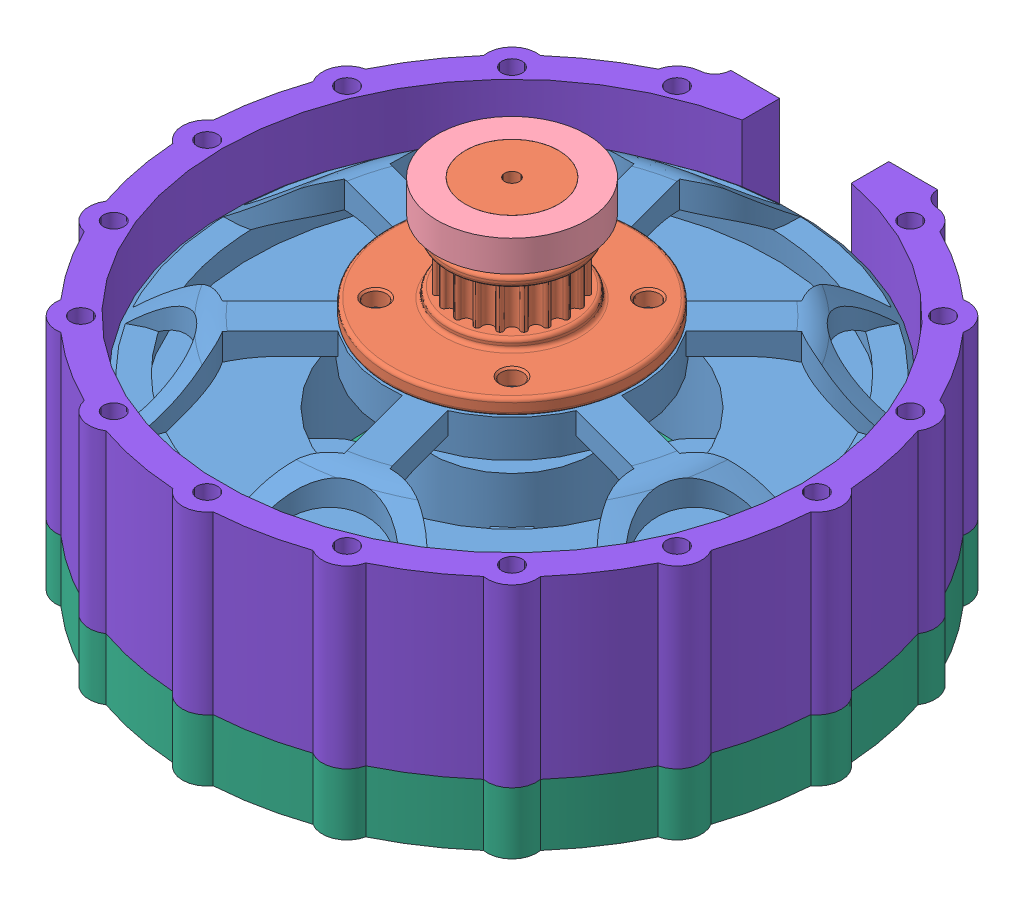
SolidWorks assembly Motor Assem, configuration Default. Lengths in mm.
Overall size (129.63 57.83 129.63).
8 component instances, 8 part files, 16 mates.
Components (placement in the parent):
- 9225 160kv-1: 9225 160kv [Default] at (0 -18.055 0) x (0.707107 0 0.707107) z (-0.707107 0 0.707107) size (91.66 44.53 91.66)
- 15 tooth htd 3mm pulley-1: 15 tooth htd 3mm pulley [Default] at (0 21.7525 0) x (0.707107 0 0.707107) z (-0.707107 0 0.707107) size (39.69 19.3 39.69)
- Encoder Magnet-1: Encoder Magnet [Default] at (0 -19.6425 0) size (6.35 3.17 6.35)
- Bearing 15_24_5mm-1: Bearing 15_24_5mm [Default] at (0 30.9275 0) size (24 5 24)
- Magnut hex puck-1: Magnut hex puck [Default] at (0 -18.055 0) x (0.707107 0 0.707107) z (-0.707107 0 0.707107) size (22.91 4.76 22.91)
- Motor Bracket Base-1: Motor Bracket Base [Default] at origin size (105.95 14.23 104.77)
- encoder final board-1: encoder final board [Default] at (0 -23.0237 -0.3766) x (0 0 -1) z (1 0 0) size (25.25 2.95 25)
- Part1-1: Part1 [Default] at origin size (105.95 28.25 104.77)
Mates (geometry in assembly coordinates):
- Coincident6: coincident anti-aligned: plane of 9225 160kv-1 through (0 -18.055 0) normal (0 -1 0); circle of Encoder Magnet-1
- Concentric2: concentric aligned: cylinder of Encoder Magnet-1 through (0 -18.055 0) axis (0 -1 0) radius 3.175
- Coincident7: coincident aligned: plane of Encoder Magnet-1 through (0 -19.6425 0) normal (0 0 1)
- Concentric4: concentric anti-aligned: cylinder of 9225 160kv-1 through (0 20.125 0) axis (0 1 0) radius 45.83
- Parallel2: parallel anti-aligned: plane of 9225 160kv-1 through (-3.25 -24.405 -36.33) normal (0 0 -1)
- Symmetric1: symmetric aligned: plane of 9225 160kv-1 through (22.981 14.125 22.981) normal (0 1 0); plane of 9225 160kv-1 through (6.8236 -14.125 6.8236) normal (0 -1 0)
- Concentric5: concentric aligned: cylinder of Bearing 15_24_5mm-1 through (0 33.4275 0) axis (0 -1 0) radius 7.5
- Coincident13: coincident anti-aligned: plane of 15 tooth htd 3mm pulley-1 through (0 24.3 0) normal (0 1 0); plane of Bearing 15_24_5mm-1 through (0 24.3 0) normal (0 -1 0)
- Coincident15: coincident aligned: line of 15 tooth htd 3mm pulley-1 through (6.6 0 25.0525) axis (0 0 -1)
- Coincident16: coincident aligned: plane of Bearing 15_24_5mm-1 through (0 30.9275 0) normal (0 0 1)
- Coincident17: coordinate: point of 9225 160kv-1; point of Magnut hex puck-1
- Coincident19: coordinate: point of assembly; point of Motor Bracket Base-1; point of assembly
- Coincident20: coincident anti-aligned: plane of 15 tooth htd 3mm pulley-1 through (5.3033 28.4275 -5.3033) normal (0 1 0); plane of Bearing 15_24_5mm-1 through (0 28.4275 0) normal (0 -1 0)
- Coincident23: coincident anti-aligned: plane of 9225 160kv-1 through (22.981 14.125 22.981) normal (0 1 0); plane of 15 tooth htd 3mm pulley-1 through (0 14.125 0) normal (0 -1 0)
- Coincident24: coincident aligned: plane of encoder final board-1 through (0 -23.0237 -0.3766) normal (1 0 0)
- Distance1: distance = 0.7937 mm anti-aligned: plane of encoder final board-1 through (0 -22.0238 -0.3766) normal (0 1 0); plane of Encoder Magnet-1 through (0 -21.23 0) normal (0 -1 0)
